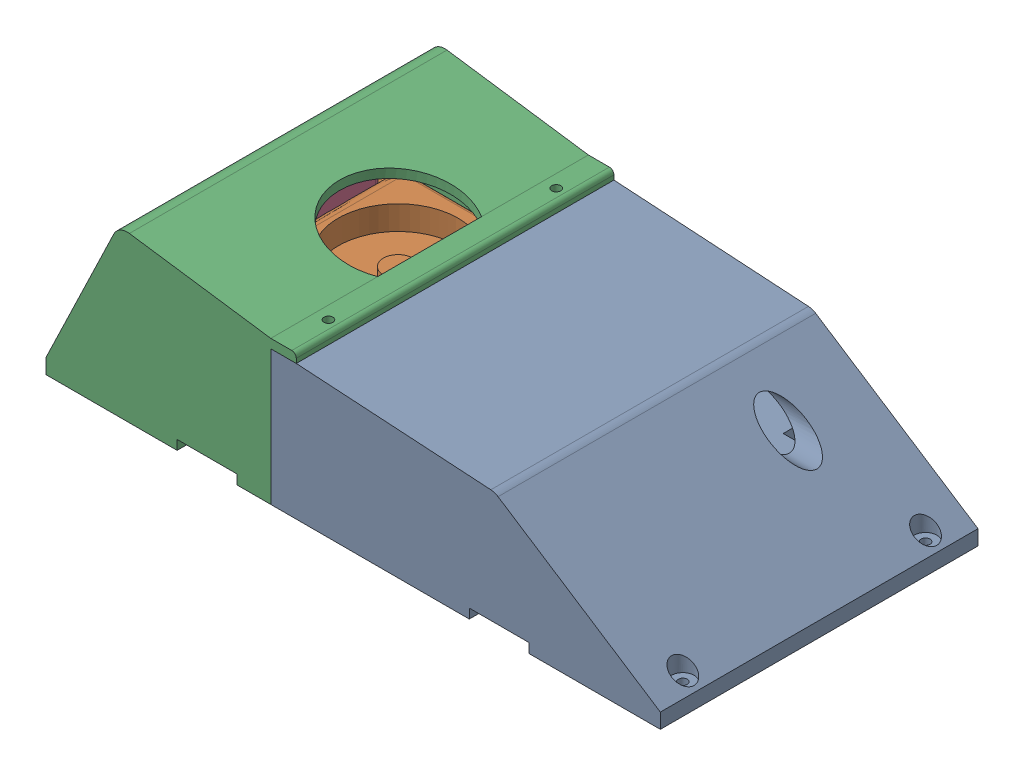
SolidWorks assembly BMS mount V2 ASSY, configuration Default. Lengths in mm.
Overall size (410 109.56 212).
4 component instances, 4 part files, 9 mates.
Components (placement in the parent):
- BMS mount V2 1-2-1: BMS mount V2 1-2 [Default] at (96.8605 -30.9054 -98.0884) size (260 90 212)
- DALY BMS-1: DALY BMS [Default] at (-122.6241 17.5946 7.9116) x (0 0 -1) z (1 0 0) size (144 53.25 255)
- BMS mount V2 2-2-1: BMS mount V2 2-2 [Default] at (-146.1241 65.0946 -98.0884) size (167.02 109.56 212)
- Balancer-2: Balancer [Default] at (-264.9241 36.363 7.9116) x (0 0 -1) z (0 -1 0) size (115 18.8 65)
Mates (geometry in assembly coordinates):
- Coincident1: coincident anti-aligned: plane of BMS mount V2 1-2-1 through (47.7024 -0.9054 113.9116) normal (0 1 0); plane of DALY BMS-1 through (-122.6241 -0.9054 -42.0884) normal (0 -1 0)
- Concentric1: concentric aligned: circle of BMS mount V2 1-2-1; circle of DALY BMS-1
- Parallel1: parallel aligned: plane of BMS mount V2 1-2-1 through (96.8605 -30.9054 -98.0884) normal (0 0 -1); plane of DALY BMS-1 through (-127.1241 5.0946 -52.0884) normal (0 0 -1)
- Coincident11: coincident aligned: plane of BMS mount V2 1-2-1 through (96.8605 -30.9054 113.9116) normal (0 0 1); plane of BMS mount V2 2-2-1 through (-146.1241 65.0946 113.9116) normal (0 0 1)
- Coincident13: coincident anti-aligned: plane of DALY BMS-1 through (-122.6241 -0.9054 -42.0884) normal (0 -1 0); plane of BMS mount V2 2-2-1 through (-163.1441 -0.9054 113.9116) normal (0 1 0)
- Coincident14: coincident anti-aligned: plane of BMS mount V2 1-2-1 through (-146.1241 -10.9054 113.9116) normal (-1 0 0); plane of BMS mount V2 2-2-1 through (-146.1241 -5.9054 113.9116) normal (1 0 0)
- Coincident17: coincident anti-aligned: plane of BMS mount V2 2-2-1 through (-264.9241 -0.9054 113.9116) normal (1 0 0); plane of Balancer-2 through (-264.9241 36.363 7.9116) normal (-1 0 0)
- Concentric3: concentric aligned: circle of BMS mount V2 2-2-1; circle of Balancer-2
- Concentric4: concentric anti-aligned: circle of BMS mount V2 2-2-1; circle of Balancer-2
